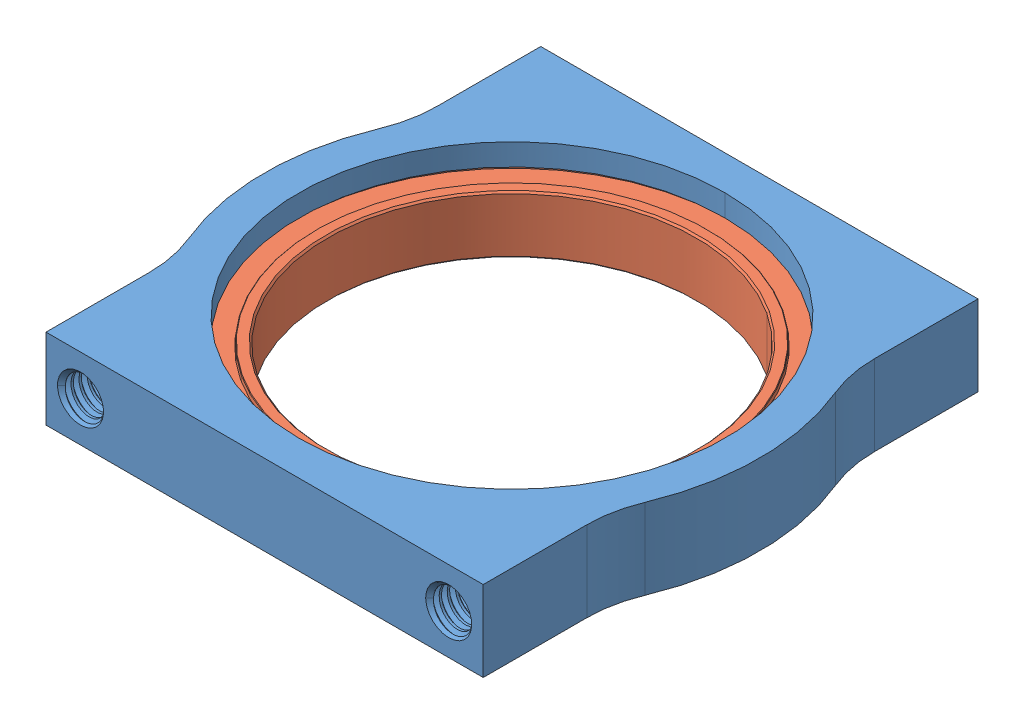
SolidWorks assembly 1604-0043-0032 assembly, configuration Default. Lengths in mm.
Overall size (56.75 7 56.75).
3 component instances, 2 part files, 0 mates.
Components (placement in the parent):
- 1604-0043-0032 assembly.STEP-1: 1604-0043-0032 assembly.STEP [Default] at origin size (56.75 7 56.75)
  - 1604-0043-0032.STEP-1: 1604-0043-0032.STEP [Default] at (-22.769 20.4479 -4.255) size (43 7 43.01)
  - 1601-0039-00032.STEP-1: 1601-0039-00032.STEP [Default] at (-22.769 22.9479 -4.255) x (-0.837169 0 -0.546944) z (-0.546944 0 0.837169) size (41 5 41)
